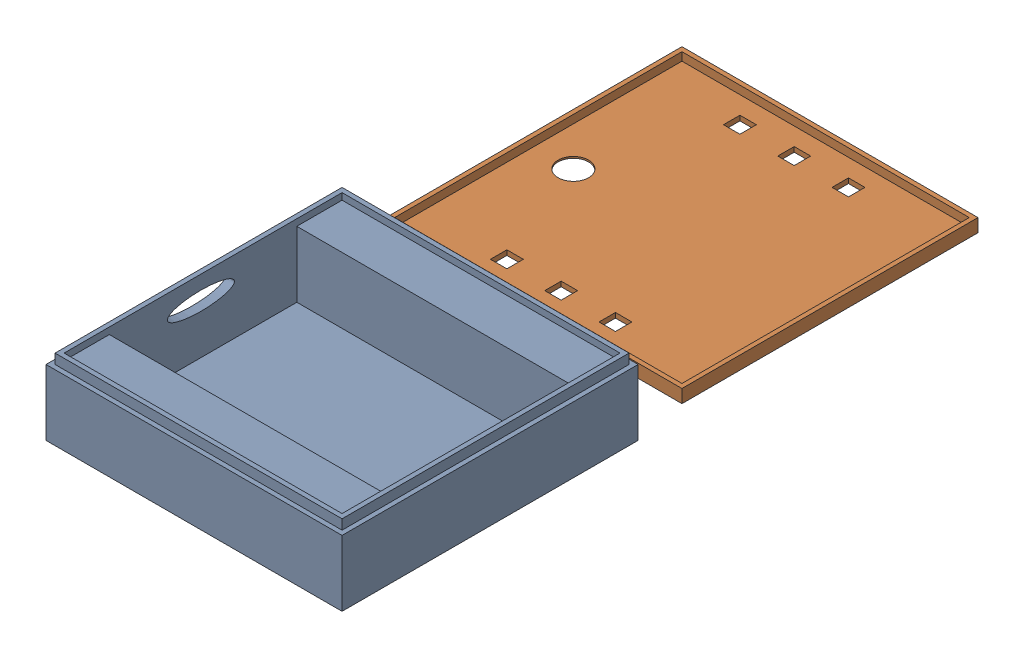
SolidWorks assembly 3d Print Assembly, configuration Default. Lengths in mm.
Overall size (92.79 23 196.12).
2 component instances, 2 part files, 0 mates.
Components (placement in the parent):
- DecibilityBox2-1: DecibilityBox2 [Default] at (-8.441 -5.9458 8.4937) size (90 23 90)
- DecibilityBox Lid-1: DecibilityBox Lid [Default] at (-11.2349 -5.7273 -97.6272) size (90 4 90)
